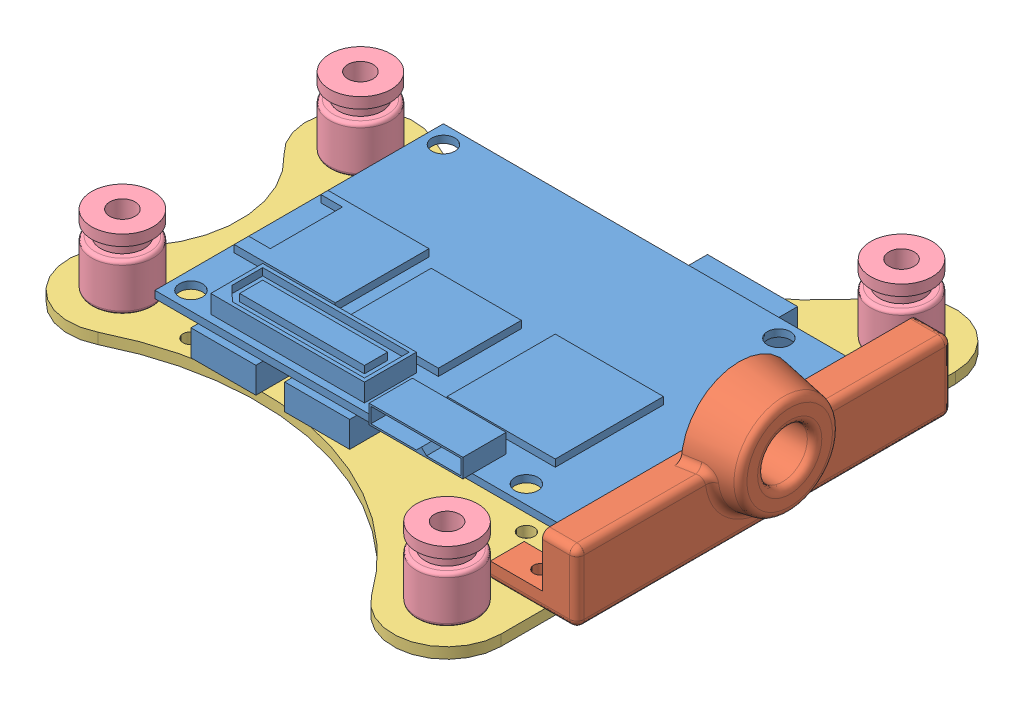
SolidWorks assembly Snapdragon_Flight, configuration Default. Lengths in mm.
Overall size (83.5 20.95 78).
7 component instances, 4 part files, 17 mates.
Components (placement in the parent):
- Snapdragon_Flight-1: Snapdragon_Flight [Default] at origin size (58 8.6 44.9)
- camera_mount-1: camera_mount [Default] at (30.7 0.1 0) x (0 0 -1) z (1 0 0) size (52 19.7 28)
- mounting_plate-1: mounting_plate [Default] at (-7 -6.25 0) x (0 0 1) z (-1 0 0) size (78 1.5 75)
- dampener-1: dampener [Default] at (23 -1.5 31.5) x (0 1 0) z (-0.237855 0 0.971301) size (13 8.5 8.5)
- dampener-2: dampener [Default] at (23 -1.5 -31.5) x (0 -1 0) z (-0.03144 0 0.999506) size (13 8.5 8.5)
- dampener-3: dampener [Default] at (-37 -1.5 -16.5) x (0 -1 0) z (0 0 1) size (13 8.5 8.5)
- dampener-4: dampener [Default] at (-37 -1.5 16.5) x (0 -1 0) z (0 0 1) size (13 8.5 8.5)
Mates (geometry in assembly coordinates):
- Coincident1: coincident aligned: plane of Snapdragon_Flight-1 through (0 0 0) normal (0 0 1); plane of assembly through (0 0 0) normal (0 0 1)
- Coincident2: coincident aligned: plane of Snapdragon_Flight-1 through (0 0 0) normal (0 1 0); plane of assembly through (0 0 0) normal (0 1 0)
- Coincident3: coincident aligned: plane of Snapdragon_Flight-1 through (0 0 0) normal (1 0 0); plane of assembly through (0 0 0) normal (1 0 0)
- Coincident6: coincident anti-aligned: plane of Snapdragon_Flight-1 through (0 0 0) normal (0 0 1); plane of camera_mount-1 through (30.7 0.1 0) normal (0 0 -1)
- Concentric2: concentric aligned: cylinder of Snapdragon_Flight-1 through (20 0 17.5) axis (0 1 0) radius 1.6; cylinder of mounting_plate-1 through (20 -6.25 17.5) axis (0 1 0) radius 1.1
- Concentric5: concentric aligned: cylinder of Snapdragon_Flight-1 through (20 0 -17.5) axis (0 1 0) radius 1.6; cylinder of mounting_plate-1 through (20 -6.25 -17.5) axis (0 1 0) radius 1.1
- Distance3: distance = 4.75 mm anti-aligned: plane of mounting_plate-1 through (23 -4.75 -31.5) normal (0 1 0); plane of Snapdragon_Flight-1 through (0 0 0) normal (0 -1 0)
- Concentric8: concentric aligned: cylinder of camera_mount-1 through (28 -6.75 23.5) axis (0 1 0) radius 1; cylinder of mounting_plate-1 through (28 -6.25 23.5) axis (0 1 0) radius 1.1
- Coincident8: coincident anti-aligned: plane of camera_mount-1 through (35.5 -4.75 26) normal (0 -1 0); plane of mounting_plate-1 through (23 -4.75 -31.5) normal (0 1 0)
- Concentric9: concentric: cylinder of mounting_plate-1 through (23 -6.25 31.5) axis (0 1 0) radius 2.5; cylinder of dampener-1 through (23 -3 31.5) axis (0 1 0) radius 3
- Concentric10: concentric: cylinder of mounting_plate-1 through (-37 -6.25 16.5) axis (0 1 0) radius 2.5; cylinder of dampener-4 through (-37 -16 16.5) axis (0 -1 0) radius 3
- Concentric11: concentric: cylinder of mounting_plate-1 through (-37 -6.25 -16.5) axis (0 1 0) radius 2.5; cylinder of dampener-3 through (-37 -16 -16.5) axis (0 -1 0) radius 3
- Concentric12: concentric: cylinder of mounting_plate-1 through (23 -6.25 -31.5) axis (0 1 0) radius 2.5; cylinder of dampener-2 through (23 -16 -31.5) axis (0 -1 0) radius 3
- Coincident17: coincident anti-aligned: plane of mounting_plate-1 through (23 -4.75 -31.5) normal (0 1 0); plane of dampener-2 through (27.2479 -4.75 -31.3664) normal (0 -1 0)
- Coincident18: coincident anti-aligned: plane of mounting_plate-1 through (23 -4.75 -31.5) normal (0 1 0); plane of dampener-3 through (-32.75 -4.75 -16.5) normal (0 -1 0)
- Coincident19: coincident anti-aligned: plane of mounting_plate-1 through (23 -4.75 -31.5) normal (0 1 0); plane of dampener-4 through (-32.75 -4.75 16.5) normal (0 -1 0)
- Coincident20: coincident anti-aligned: plane of mounting_plate-1 through (23 -4.75 -31.5) normal (0 1 0); plane of dampener-1 through (20.0861 -4.75 30.7864) normal (0 -1 0)
